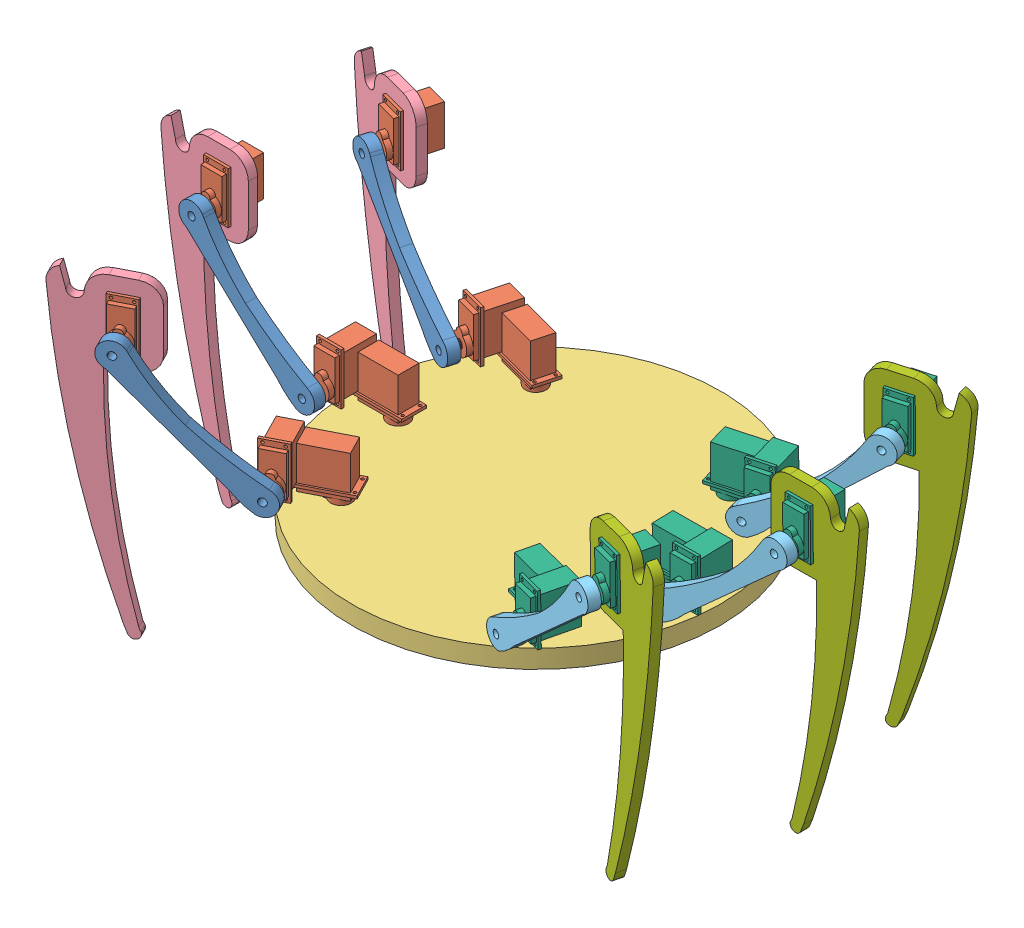
SolidWorks assembly Assembly, configuration Default. Lengths in mm.
Overall size (378.71 170 225.73).
41 component instances, 9 part files, 0 mates.
Components (placement in the parent):
- Pata2-1: Pata2 [Default] at (-131.1259 -170.0138 57.3877) x (-0.818339 0.408511 0.404276) z (-0.449641 -0.01694 -0.893049) size (91.94 38.8 6)
- Servo Turningy 9g-1: Servo Turningy 9g [Valor predeterminado] at (-146.934 -165.0366 26.3975) x (0.891007 0 -0.45399) z (0 -1 0) size (13.4 28.6 27.8)
- Servo Turningy 9g-7: Servo Turningy 9g [Valor predeterminado] at (-201.1695 -110.33 54.3133) x (0.891007 0 -0.45399) z (0 -1 0) size (13.4 28.6 27.8)
- Servo Turningy 9g-8: Servo Turningy 9g [Valor predeterminado] at (-130.1816 -157.6358 22.781) x (0.45399 0 0.891007) z (0.891007 0 -0.45399) size (13.4 28.6 27.8)
- Base-1: Base [Default] at (-72.7779 -183.5335 -32.5683) x (-1 0 0) z (0 -1 0) size (200.08 200.08 10)
- Pata-3: Pata [Default] at (-189.6842 -98.5483 63.6125) x (0 1 0) z (0.45399 0 0.891007) size (168.85 47.43 5)
- PataComplete-1: PataComplete [Default] at (-16.5797 -0.0974 -46.9942) size (122.91 168.85 37.28)
  - Pata2-1: Pata2 [Default] at (-152.6346 -170.0138 44.9187) x (-0.912683 0.408511 -0.011306) z (0.004803 -0.01694 -0.999845) size (91.94 38.8 6)
  - Servo Turningy 9g-1: Servo Turningy 9g [Valor predeterminado] at (-152.6505 -165.0366 10.1296) x (1 0 0) z (0 -1 0) size (13.4 28.6 27.8)
  - Servo Turningy 9g-7: Servo Turningy 9g [Valor predeterminado] at (-213.6482 -110.33 10.3803) x (1 0 0) z (0 -1 0) size (13.4 28.6 27.8)
  - Servo Turningy 9g-8: Servo Turningy 9g [Valor predeterminado] at (-136.0821 -157.6358 14.5126) x (0 0 1) z (1 0 0) size (13.4 28.6 27.8)
  - Pata-3: Pata [Default] at (-207.6364 -98.5483 23.8802) x (0 1 0) z (0 0 1) size (168.85 47.43 5)
- Part3^Assembly-1: Part3^Assembly [Default] at origin (virtual)
- PataComplete-2: PataComplete [Default] at (4.2558 -0.0487 -65.6972) x (0.965926 0 0.258819) z (-0.258819 0 0.965926) size (122.91 168.85 37.28)
  - Pata2-1: Pata2 [Default] at (-152.6346 -170.0138 44.9187) x (-0.912683 0.408511 -0.011306) z (0.004803 -0.01694 -0.999845) size (91.94 38.8 6)
  - Servo Turningy 9g-1: Servo Turningy 9g [Valor predeterminado] at (-152.6505 -165.0366 10.1296) x (1 0 0) z (0 -1 0) size (13.4 28.6 27.8)
  - Servo Turningy 9g-7: Servo Turningy 9g [Valor predeterminado] at (-213.6482 -110.33 10.3803) x (1 0 0) z (0 -1 0) size (13.4 28.6 27.8)
  - Servo Turningy 9g-8: Servo Turningy 9g [Valor predeterminado] at (-136.0821 -157.6358 14.5126) x (0 0 1) z (1 0 0) size (13.4 28.6 27.8)
  - Pata-3: Pata [Default] at (-207.6364 -98.5483 23.8802) x (0 1 0) z (0 0 1) size (168.85 47.43 5)
- MirrorPataComplete-26: MirrorPataComplete [Default] at (-143.1903 0.7821 -23.2668) x (-0.969085 0.004345 -0.24669) z (0.246727 0.013914 -0.968985) size (122.91 168.85 37.28)
  - MirrorPata2-1: MirrorPata2 [Default] at (-152.6346 -170.0138 -44.9187) x (-0.912683 0.408511 0.011306) z (-0.004803 0.01694 -0.999845) size (91.94 38.8 6)
  - MirrorServo Turningy 9g-1: MirrorServo Turningy 9g [Valor predeterminado] at (-152.6505 -165.0366 -10.1296) x (1 0 0) z (0 1 0) size (13.4 28.6 27.8)
  - MirrorServo Turningy 9g-2: MirrorServo Turningy 9g [Valor predeterminado] at (-213.6482 -110.33 -10.3803) x (1 0 0) z (0 1 0) size (13.4 28.6 27.8)
  - MirrorServo Turningy 9g-3: MirrorServo Turningy 9g [Valor predeterminado] at (-136.0821 -157.6358 -14.5126) x (0 0 -1) z (-1 0 0) size (13.4 28.6 27.8)
  - MirrorPata-1: MirrorPata [Default] at (-207.6364 -98.5483 -23.8802) x (0 1 0) z (0 0 1) size (168.85 47.43 5)
- PataCompleteMirrored-1: PataCompleteMirrored [Default] at (-58.4492 -27.3045 -40.3671) size (124.13 169.89 41.15)
  - Part3^PataCompleteMirrored-1: Part3^PataCompleteMirrored [Default] at origin (virtual)
  - MirrorPataComplete-26: MirrorPataComplete [Default] at (-69.7487 27.9974 -2.3661) x (-0.999912 0.004345 0.012534) z (-0.012472 0.013914 -0.999825) size (122.91 168.85 37.28)
    - MirrorPata2-1: MirrorPata2 [Default] at (-152.6346 -170.0138 -44.9187) x (-0.912683 0.408511 0.011306) z (-0.004803 0.01694 -0.999845) size (91.94 38.8 6)
    - MirrorServo Turningy 9g-1: MirrorServo Turningy 9g [Valor predeterminado] at (-152.6505 -165.0366 -10.1296) x (1 0 0) z (0 1 0) size (13.4 28.6 27.8)
    - MirrorServo Turningy 9g-2: MirrorServo Turningy 9g [Valor predeterminado] at (-213.6482 -110.33 -10.3803) x (1 0 0) z (0 1 0) size (13.4 28.6 27.8)
    - MirrorServo Turningy 9g-3: MirrorServo Turningy 9g [Valor predeterminado] at (-136.0821 -157.6358 -14.5126) x (0 0 -1) z (-1 0 0) size (13.4 28.6 27.8)
    - MirrorPata-1: MirrorPata [Default] at (-207.6364 -98.5483 -23.8802) x (0 1 0) z (0 0 1) size (168.85 47.43 5)
- PataCompleteMirrored-2: PataCompleteMirrored [Default] at (-82.4513 -27.1927 -79.4097) x (0.965926 0 -0.258819) z (0.258819 0 0.965926) size (124.13 169.89 41.15)
  - Part3^PataCompleteMirrored-1: Part3^PataCompleteMirrored [Default] at origin (virtual)
  - MirrorPataComplete-26: MirrorPataComplete [Default] at (-69.7487 27.9974 -2.3661) x (-0.999912 0.004345 0.012534) z (-0.012472 0.013914 -0.999825) size (122.91 168.85 37.28)
    - MirrorPata2-1: MirrorPata2 [Default] at (-152.6346 -170.0138 -44.9187) x (-0.912683 0.408511 0.011306) z (-0.004803 0.01694 -0.999845) size (91.94 38.8 6)
    - MirrorServo Turningy 9g-1: MirrorServo Turningy 9g [Valor predeterminado] at (-152.6505 -165.0366 -10.1296) x (1 0 0) z (0 1 0) size (13.4 28.6 27.8)
    - MirrorServo Turningy 9g-2: MirrorServo Turningy 9g [Valor predeterminado] at (-213.6482 -110.33 -10.3803) x (1 0 0) z (0 1 0) size (13.4 28.6 27.8)
    - MirrorServo Turningy 9g-3: MirrorServo Turningy 9g [Valor predeterminado] at (-136.0821 -157.6358 -14.5126) x (0 0 -1) z (-1 0 0) size (13.4 28.6 27.8)
    - MirrorPata-1: MirrorPata [Default] at (-207.6364 -98.5483 -23.8802) x (0 1 0) z (0 0 1) size (168.85 47.43 5)
